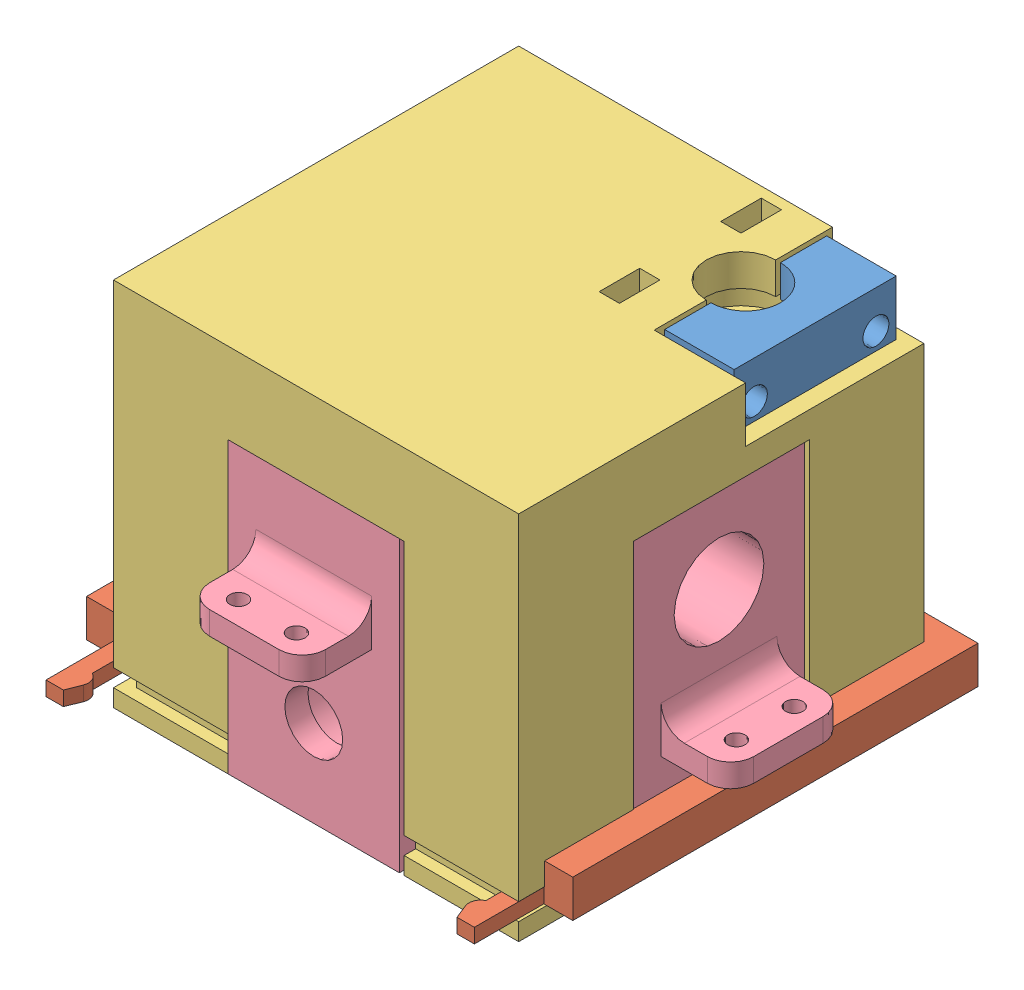
SolidWorks assembly P3DMIPC-Tête_complete, configuration Défaut. Lengths in mm.
Overall size (94 66.9 96.47).
4 component instances, 4 part files, 5 mates.
Components (placement in the parent):
- P3DMIPC-Clip_Buse_E3D-1: P3DMIPC-Clip_Buse_E3D [Défaut] at (19.0418 23.5508 38.8304) x (1 0 0) z (0 1 0) size (12 28 9.5)
- P3DMIPC-Clip_tête-1: P3DMIPC-Clip_tête [Défaut] at (26.9018 -25.0891 4.5597) x (1 0 0) z (0 -1 0) size (84 92 6.55)
- P3DMIPC-Porte_Buse_E3DX1-1: P3DMIPC-Porte_Buse_E3DX1 [Défaut] at (22.03 33.0508 79.0304) x (0 0 1) z (0 -1 0) size (77 70 66.9)
- P3DMIPC-Chariot-1: P3DMIPC-Chariot [Défaut] at (-48.37 -30.9492 79.0304) size (94 50 94)
Mates (geometry in assembly coordinates):
- Coïncidente19: coincident anti-aligned: plane of P3DMIPC-Porte_Buse_E3DX1-1 through (22.03 19.0508 79.0304) normal (0 -1 0); plane of P3DMIPC-Chariot-1 through (21.63 19.0508 79.0304) normal (0 1 0)
- Coïncidente20: coincident anti-aligned: plane of P3DMIPC-Porte_Buse_E3DX1-1 through (-28.17 19.0508 79.0304) normal (1 0 0); plane of P3DMIPC-Chariot-1 through (-28.17 19.0508 79.0304) normal (-1 0 0)
- Coïncidente21: coincident aligned: plane of P3DMIPC-Porte_Buse_E3DX1-1 through (22.03 -30.9492 79.0304) normal (0 0 1); plane of P3DMIPC-Chariot-1 through (21.63 -30.9492 79.0304) normal (0 0 1)
- Coïncidente22: coincident anti-aligned: plane of P3DMIPC-Clip_Buse_E3D-1 through (19.0418 23.5508 38.8304) normal (0 -1 0); plane of P3DMIPC-Porte_Buse_E3DX1-1 through (22.03 23.5508 79.0304) normal (0 1 0)
- Coaxiale1: concentric anti-aligned: cylinder of P3DMIPC-Clip_Buse_E3D-1 through (19.0418 26.5508 14.3304) axis (-1 0 0) radius 2.25; cylinder of P3DMIPC-Porte_Buse_E3DX1-1 through (-8.77 26.5508 14.3304) axis (1 0 0) radius 2.25
